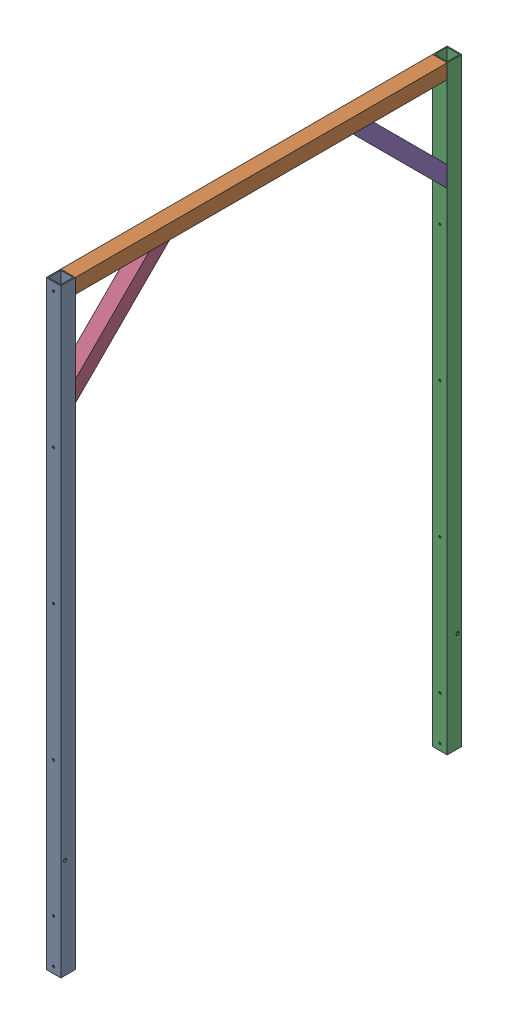
SolidWorks assembly GE-16161_ASM, configuration Default. Lengths in mm.
Overall size (44.45 1828.8 1223.26).
5 component instances, 3 part files, 0 mates.
Components (placement in the parent):
- GE-16161-01-1: GE-16161-01 [Default] at origin size (44.45 1828.8 44.45)
- GE-16161-02-1: GE-16161-02 [Default] at (-22.225 1784.35 -1156.589) size (44.45 44.45 1134.36)
- GE-16161-01-2: GE-16161-01 [Default] at (0 0 -1178.814) x (-1 0 0) z (0 0 -1) size (44.45 1828.8 44.45)
- GE-16161-03-1: GE-16161-03 [Default] at (-22.225 1784.35 -246.7314) x (1 0 0) z (0 0.707107 -0.707107) size (44.45 44.45 406.4)
- GE-16161-03-2: GE-16161-03 [Default] at (-22.225 1559.8436 -1156.589) x (1 0 0) z (0 -0.707107 -0.707107) size (44.45 44.45 406.4)
